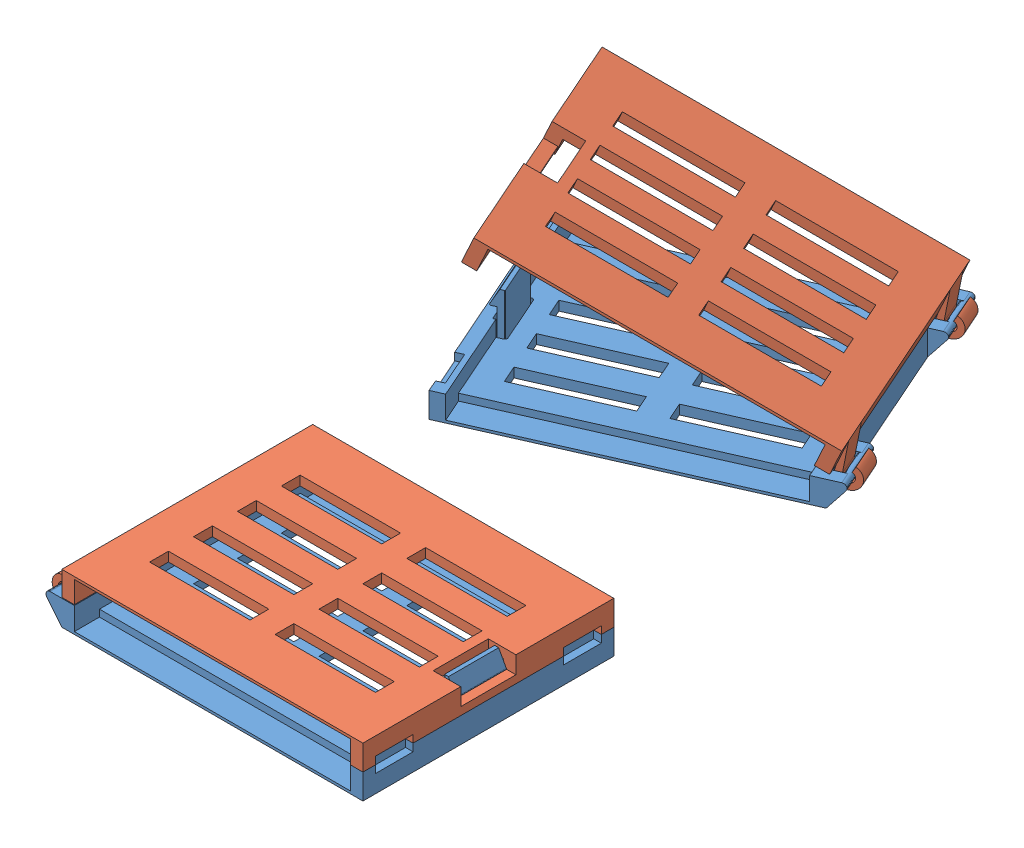
SolidWorks assembly Assem1, configuration Default. Lengths in mm.
Overall size (103.07 41.96 184.3).
6 component instances, 2 part files, 1 mates.
Components (placement in the parent):
- cableCaseAssembly-1: cableCaseAssembly [Default] at (-74.7458 -1.0718 35.7849) size (82.07 12.7 63.5) (flexible)
  - cableCase_bottom-1: cableCase_bottom [Default] at (-19.1198 -11.2674 17.3021) size (80.2 12.7 63.5)
  - cableCase_top-1: cableCase_top [Default] at (-19.1198 -8.0924 17.3021) size (82.07 10.22 63.5)
- cableCaseAssembly-2: cableCaseAssembly [Default] at (-119.512 -1.0718 -28.0757) x (-0.914801 0 0.403904) z (-0.403904 0 -0.914801) size (84.63 41.96 63.5) (flexible)
  - cableCase_bottom-1: cableCase_bottom [Default] at (-19.1198 -11.2674 17.3021) size (80.2 12.7 63.5)
  - cableCase_top-1: cableCase_top [Default] at (-22.5162 7.298 17.3021) x (0.926518 0.37625 0) z (0 0 1) size (82.07 10.22 63.5)
Mates (geometry in assembly coordinates):
- Coincident1: coincident aligned: plane of cableCaseAssembly-1/cableCase_bottom-1 through (-93.8656 -15.5142 84.837) normal (0 -1 0); plane of cableCaseAssembly-2/cableCase_bottom-1 through (-121.8335 -15.5142 -80.6713) normal (0 -1 0)
